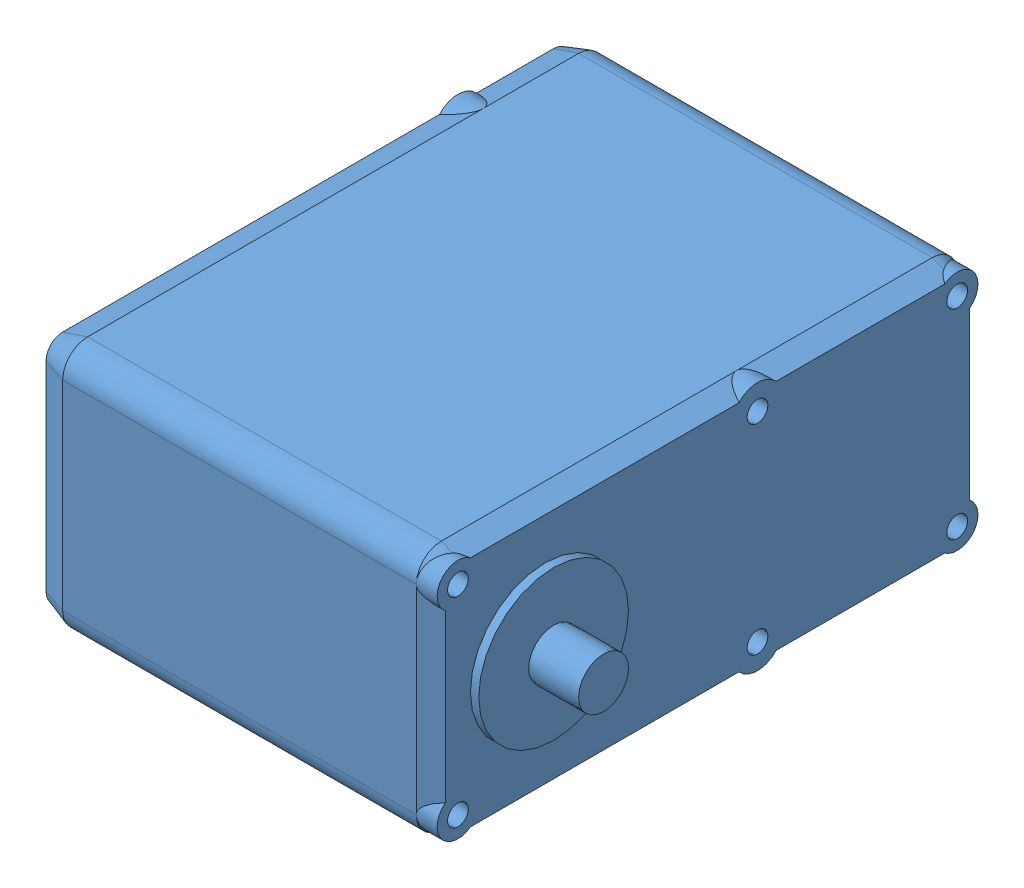
SolidWorks assembly 80KGServo, configuration Default. Lengths in mm.
Overall size (62 30 65).
2 component instances, 2 part files, 0 mates.
Components (placement in the parent):
- 80KGServoBase-1: 80KGServoBase [Default] at (5.982 18.4775 59.8406) size (56 30 65)
- 80KGServoShaft-1: 80KGServoShaft [Default] at (-19.018 33.4775 79.3406) x (0 -0.922672 -0.385587) z (0 0.385587 -0.922672) size (8 6 8)
